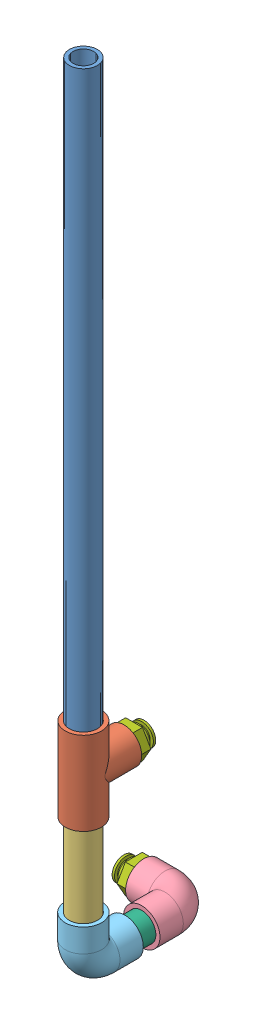
SolidWorks assembly manifold_outlet, configuration Default. Lengths in mm.
Overall size (61.44 612.55 106.13).
8 component instances, 7 part files, 19 mates.
Components (placement in the parent):
- pvc-050-018-1: pvc-050-018 [Default] at (35.6535 21.7852 78.3315) size (21.34 457.2 21.34)
- threaded_tee-1: threaded_tee [4880K392] at (35.6535 9.5932 78.3315) x (0 1 0) z (-1 0 0) size (63.5 45.17 27.56)
- pvc-050-004-1: pvc-050-004 [Default] at (35.6535 -104.1988 78.3315) size (21.34 101.6 21.34)
- my90-1: my90 [Default] at (5.491 -116.8988 2.1315) x (0 -1 0) z (-1 0 0) size (27.78 45.64 44.99)
- unthreaded 90-1: unthreaded 90 [Default] at (35.6535 -85.1488 78.3315) x (1 0 0) z (0 1 0) size (27.78 45.64 45.64)
- pvc-050-002-1: pvc-050-002 [Default] at (35.6535 -116.8988 65.6315) x (1 0 0) z (0 1 0) size (21.34 50.8 21.34)
- connector_orange-1: connector_orange [Default] at (5.491 -116.8988 2.1315) x (0 0.866025 0.5) z (0 -0.5 0.866025) size (25.66 23.29 22.23)
- connector_orange-2: connector_orange [Default] at (35.6535 9.5932 47.3435) x (0.5 -0.866025 0) z (0.866025 0.5 0) size (25.66 23.29 22.23)
Mates (geometry in assembly coordinates):
- Concentric1: concentric anti-aligned: circle of pvc-050-018-1; circle of threaded_tee-1
- Coincident1: coincident anti-aligned: plane of pvc-050-018-1 through (35.6535 21.7852 78.3315) normal (0 -1 0); plane of threaded_tee-1 through (35.6535 21.7852 78.3315) normal (0 1 0)
- Parallel2: parallel anti-aligned: plane of threaded_tee-1 through (35.6535 23.0298 47.3435) normal (0 0 -1); plane of assembly through (0 0 0) normal (0 0 1)
- Concentric2: concentric anti-aligned: circle of threaded_tee-1; circle of pvc-050-004-1
- Coincident3: coincident anti-aligned: plane of threaded_tee-1 through (35.6535 -2.5988 78.3315) normal (0 -1 0); plane of pvc-050-004-1 through (35.6535 -2.5988 78.3315) normal (0 1 0)
- Concentric3: concentric aligned: circle of pvc-050-004-1; circle of unthreaded 90-1
- Coincident4: coincident anti-aligned: plane of pvc-050-004-1 through (35.6535 -104.1988 78.3315) normal (0 -1 0); plane of unthreaded 90-1 through (35.6535 -104.1988 78.3315) normal (0 1 0)
- Parallel3: parallel aligned: plane of threaded_tee-1 through (35.6535 23.0298 47.3435) normal (0 0 -1); plane of unthreaded 90-1 through (35.6535 -116.8988 46.5815) normal (0 0 -1)
- Coincident6: coincident anti-aligned: plane of unthreaded 90-1 through (35.6535 -116.8988 65.6315) normal (0 0 -1); plane of pvc-050-002-1 through (35.6535 -116.8988 65.6315) normal (0 0 1)
- Concentric4: concentric aligned: circle of unthreaded 90-1; circle of pvc-050-002-1
- Concentric5: concentric aligned: circle of pvc-050-002-1; circle of my90-1
- Coincident7: coincident anti-aligned: plane of my90-1 through (35.6535 -116.8988 14.8315) normal (0 0 1); plane of pvc-050-002-1 through (35.6535 -116.8988 14.8315) normal (0 0 -1)
- Perpendicular2: perpendicular: plane of my90-1 through (5.491 -116.8988 2.1315) normal (-1 0 0); plane of unthreaded 90-1 through (35.6535 -85.1488 78.3315) normal (0 1 0)
- Concentric6: concentric anti-aligned: circle of my90-1; circle of connector_orange-1
- Coincident11: coincident anti-aligned: plane of my90-1 through (5.491 -116.8988 2.1315) normal (-1 0 0); plane of connector_orange-1 through (5.491 -116.8988 2.1315) normal (1 0 0)
- Parallel6: parallel aligned: plane of unthreaded 90-1 through (35.6535 -85.1488 78.3315) normal (0 1 0); plane of connector_orange-1 through (-2.129 -105.7863 8.5473) normal (0 1 0)
- Concentric7: concentric anti-aligned: circle of threaded_tee-1; circle of connector_orange-2
- Coincident13: coincident anti-aligned: plane of threaded_tee-1 through (35.6535 23.0298 47.3435) normal (0 0 -1); plane of connector_orange-2 through (35.6535 9.5932 47.3435) normal (0 0 1)
- Parallel7: parallel aligned: plane of threaded_tee-1 through (35.6535 -22.1568 92.111) normal (0 -1 0); plane of connector_orange-2 through (42.0694 -1.5193 39.7235) normal (0 -1 0)
